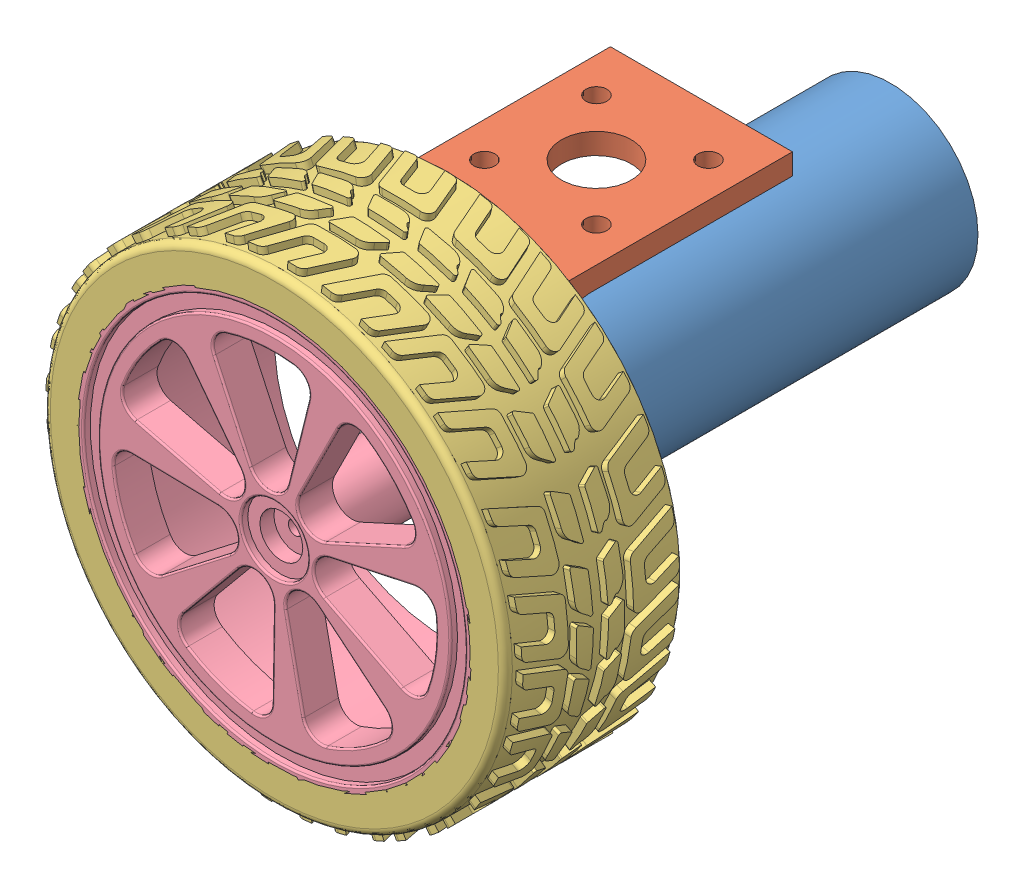
SolidWorks assembly Assem2, configuration Default. Lengths in mm.
Overall size (68.01 68.01 88).
5 component instances, 4 part files, 4 mates.
Components (placement in the parent):
- motor-1: motor [Default] at (-90.4425 -13.6311 26.9861) size (25 25 60)
- bracket-1: bracket [Default] at (-77.4425 7.3689 53.9861) x (0 0 1) z (-1 0 0) size (36 37 26)
- Wheel Assemble-1: Wheel Assemble [默认] at (-90.4425 -13.6311 90.0941) size (68.01 68.01 25)
  - Tire-1: Tire [默认] at origin size (68.01 68.01 24.89)
  - WheelFrame-2: WheelFrame [默认] at (-797.8323 -276.5666 -0.108) size (56.38 56.38 25)
Mates (geometry in assembly coordinates):
- Concentric1: concentric aligned: cylinder of motor-1 through (-90.4425 -13.6311 86.9861) axis (0 0 -1) radius 12.5; cylinder of Wheel Assemble-1/WheelFrame-2 through (-90.4425 -13.6311 109.9861) axis (0 0 -1) radius 5
- Concentric2: concentric anti-aligned: cylinder of motor-1 through (-90.4425 -13.6311 86.9861) axis (0 0 -1) radius 12.5; cylinder of bracket-1 through (-90.4425 -13.6311 63.9861) axis (0 0 1) radius 4
- Coincident1: coincident anti-aligned: plane of motor-1 through (-90.4425 -13.6311 86.9861) normal (0 0 1); plane of bracket-1 through (-103.4425 7.3689 86.9861) normal (0 0 -1)
- Coincident2: coincident anti-aligned: plane of bracket-1 through (-103.4425 10.3689 89.9861) normal (0 0 1); plane of Wheel Assemble-1/WheelFrame-2 through (-90.4425 -13.6311 89.9861) normal (0 0 -1)
